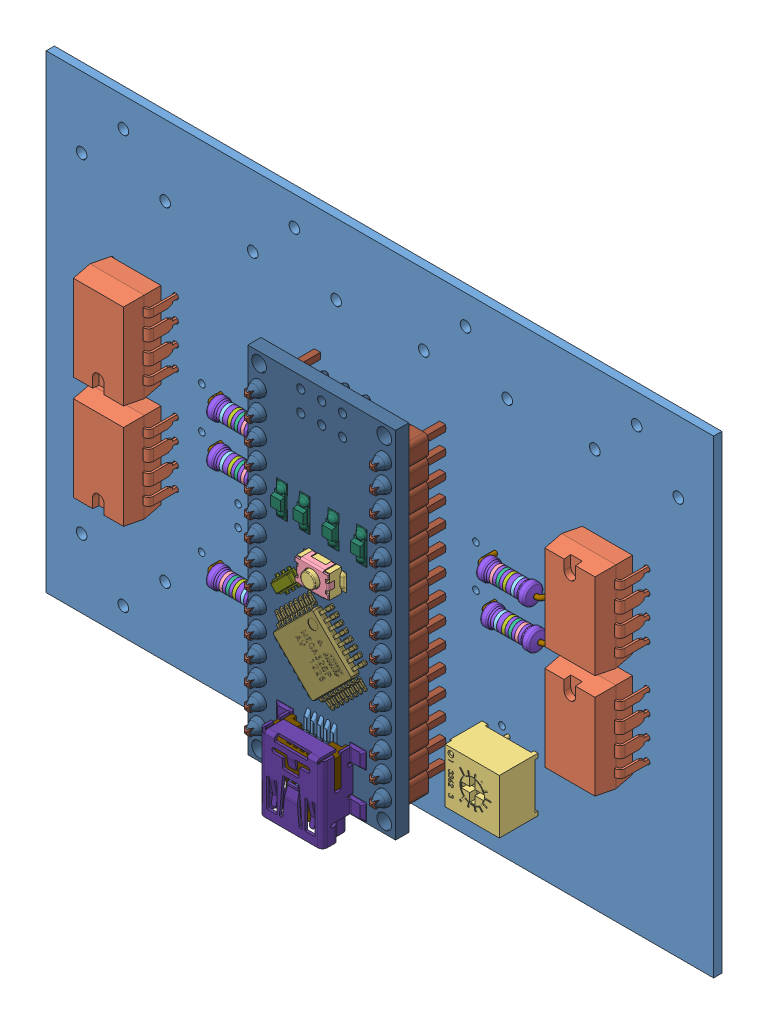
SolidWorks assembly main1, configuration По умолчанию. Lengths in mm.
Overall size (81.26 57.14 14.93).
72 component instances, 26 part files, 23 mates.
Components (placement in the parent):
- main-1: main [По умолчанию] at origin size (81.26 57.14 1)
- DIP 8 IC-1: DIP 8 IC [Default] at (116.08 60.84 1.5) size (7.87 10.92 8.58)
- DIP 8 IC-2: DIP 8 IC [Default] at (116.08 48.14 1.5) size (7.87 10.92 8.58)
- DIP 8 IC-3: DIP 8 IC [Default] at (58.67 47.88 1.5) x (-1 0 0) z (0 0 1) size (7.87 10.92 8.58)
- DIP 8 IC-4: DIP 8 IC [Default] at (58.67 60.58 1.5) x (-1 0 0) z (0 0 1) size (7.87 10.92 8.58)
- 3362H-1: 3362H [Default] at (104.78 36.58 2.47) x (0 -1 0) z (0 0 1) size (6.6 7.05 10.17)
- User Library-CFR-25 CFR50S (300mils)-2-1: User Library-CFR-25 CFR50S (300mils)-2 [Default] at (71.8501 39.141 2.5768) x (0 0 -1) z (0.999985 -0.0055 0) size (5.28 2.4 8.17)
  - User Library-CFR-25 CFR50S (300mils)-2_Band1-1: User Library-CFR-25 CFR50S (300mils)-2_Band1 [Default] at origin size (2.01 2.01 0.4)
  - User Library-CFR-25 CFR50S (300mils)-2_Band4-1: User Library-CFR-25 CFR50S (300mils)-2_Band4 [Default] at origin size (2.01 2.01 0.4)
  - User Library-CFR-25 CFR50S (300mils)-2_Band2-1: User Library-CFR-25 CFR50S (300mils)-2_Band2 [Default] at origin size (2.01 2.01 0.4)
  - User Library-CFR-25 CFR50S (300mils)-2_Band3-1: User Library-CFR-25 CFR50S (300mils)-2_Band3 [Default] at origin size (2.01 2.01 0.4)
  - User Library-CFR-25 CFR50S (300mils)-2_Core-1: User Library-CFR-25 CFR50S (300mils)-2_Core [Default] at origin size (2.4 2.4 6.3)
  - User Library-CFR-25 CFR50S (300mils)-2_Leads-1: User Library-CFR-25 CFR50S (300mils)-2_Leads [Default] at origin size (4.35 0.55 8.17)
- User Library-CFR-25 CFR50S (300mils)-2-2: User Library-CFR-25 CFR50S (300mils)-2 [Default] at (105.2501 51.7882 2.5768) x (0 0 -1) z (-0.999965 -0.008347 0) size (5.28 2.4 8.17)
  - User Library-CFR-25 CFR50S (300mils)-2_Band1-1: User Library-CFR-25 CFR50S (300mils)-2_Band1 [Default] at origin size (2.01 2.01 0.4)
  - User Library-CFR-25 CFR50S (300mils)-2_Band4-1: User Library-CFR-25 CFR50S (300mils)-2_Band4 [Default] at origin size (2.01 2.01 0.4)
  - User Library-CFR-25 CFR50S (300mils)-2_Band2-1: User Library-CFR-25 CFR50S (300mils)-2_Band2 [Default] at origin size (2.01 2.01 0.4)
  - User Library-CFR-25 CFR50S (300mils)-2_Band3-1: User Library-CFR-25 CFR50S (300mils)-2_Band3 [Default] at origin size (2.01 2.01 0.4)
  - User Library-CFR-25 CFR50S (300mils)-2_Core-1: User Library-CFR-25 CFR50S (300mils)-2_Core [Default] at origin size (2.4 2.4 6.3)
  - User Library-CFR-25 CFR50S (300mils)-2_Leads-1: User Library-CFR-25 CFR50S (300mils)-2_Leads [Default] at origin size (4.35 0.55 8.17)
- User Library-CFR-25 CFR50S (300mils)-2-3: User Library-CFR-25 CFR50S (300mils)-2 [Default] at (71.8802 56.9346 2.5768) x (0 0 -1) z (-0.999959 0.009082 0) size (5.28 2.4 8.17)
  - User Library-CFR-25 CFR50S (300mils)-2_Band1-1: User Library-CFR-25 CFR50S (300mils)-2_Band1 [Default] at origin size (2.01 2.01 0.4)
  - User Library-CFR-25 CFR50S (300mils)-2_Band4-1: User Library-CFR-25 CFR50S (300mils)-2_Band4 [Default] at origin size (2.01 2.01 0.4)
  - User Library-CFR-25 CFR50S (300mils)-2_Band2-1: User Library-CFR-25 CFR50S (300mils)-2_Band2 [Default] at origin size (2.01 2.01 0.4)
  - User Library-CFR-25 CFR50S (300mils)-2_Band3-1: User Library-CFR-25 CFR50S (300mils)-2_Band3 [Default] at origin size (2.01 2.01 0.4)
  - User Library-CFR-25 CFR50S (300mils)-2_Core-1: User Library-CFR-25 CFR50S (300mils)-2_Core [Default] at origin size (2.4 2.4 6.3)
  - User Library-CFR-25 CFR50S (300mils)-2_Leads-1: User Library-CFR-25 CFR50S (300mils)-2_Leads [Default] at origin size (4.35 0.55 8.17)
- User Library-CFR-25 CFR50S (300mils)-2-4: User Library-CFR-25 CFR50S (300mils)-2 [Default] at (71.88 51.82 2.5768) x (0 0 -1) z (-1 0 0) size (5.28 2.4 8.17)
  - User Library-CFR-25 CFR50S (300mils)-2_Band1-1: User Library-CFR-25 CFR50S (300mils)-2_Band1 [Default] at origin size (2.01 2.01 0.4)
  - User Library-CFR-25 CFR50S (300mils)-2_Band4-1: User Library-CFR-25 CFR50S (300mils)-2_Band4 [Default] at origin size (2.01 2.01 0.4)
  - User Library-CFR-25 CFR50S (300mils)-2_Band2-1: User Library-CFR-25 CFR50S (300mils)-2_Band2 [Default] at origin size (2.01 2.01 0.4)
  - User Library-CFR-25 CFR50S (300mils)-2_Band3-1: User Library-CFR-25 CFR50S (300mils)-2_Band3 [Default] at origin size (2.01 2.01 0.4)
  - User Library-CFR-25 CFR50S (300mils)-2_Core-1: User Library-CFR-25 CFR50S (300mils)-2_Core [Default] at origin size (2.4 2.4 6.3)
  - User Library-CFR-25 CFR50S (300mils)-2_Leads-1: User Library-CFR-25 CFR50S (300mils)-2_Leads [Default] at origin size (4.35 0.55 8.17)
- User Library-CFR-25 CFR50S (300mils)-2-5: User Library-CFR-25 CFR50S (300mils)-2 [Default] at (105.25 56.9167 3.0768) x (0 0 -1) z (0.99999 -0.004388 0) size (5.28 2.4 8.17)
  - User Library-CFR-25 CFR50S (300mils)-2_Band1-1: User Library-CFR-25 CFR50S (300mils)-2_Band1 [Default] at origin size (2.01 2.01 0.4)
  - User Library-CFR-25 CFR50S (300mils)-2_Band4-1: User Library-CFR-25 CFR50S (300mils)-2_Band4 [Default] at origin size (2.01 2.01 0.4)
  - User Library-CFR-25 CFR50S (300mils)-2_Band2-1: User Library-CFR-25 CFR50S (300mils)-2_Band2 [Default] at origin size (2.01 2.01 0.4)
  - User Library-CFR-25 CFR50S (300mils)-2_Band3-1: User Library-CFR-25 CFR50S (300mils)-2_Band3 [Default] at origin size (2.01 2.01 0.4)
  - User Library-CFR-25 CFR50S (300mils)-2_Core-1: User Library-CFR-25 CFR50S (300mils)-2_Core [Default] at origin size (2.4 2.4 6.3)
  - User Library-CFR-25 CFR50S (300mils)-2_Leads-1: User Library-CFR-25 CFR50S (300mils)-2_Leads [Default] at origin size (4.35 0.55 8.17)
- User Library-arduino_nano-1: User Library-arduino_nano [Default] at (79.76 67.06 6.5) x (0 -1 0) z (-1 0 0) size (45 13.93 18)
  - User Library-arduino_nano_nano-board-1: User Library-arduino_nano_nano-board [Default] at origin size (43.2 4.6 18)
  - User Library-arduino_nano_15pin_header__-1: User Library-arduino_nano_15pin_header__ [Default] x (0 0 1) z (1 0 0) size (2.54 11.75 38.1)
  - User Library-arduino_nano_15pin_header__-2: User Library-arduino_nano_15pin_header__ [Default] at (0 0 -15.24) x (0 0 1) z (1 0 0) size (2.54 11.75 38.1)
  - User Library-arduino_nano_atmega328-1: User Library-arduino_nano_atmega328 [Default] at (23.85 1.75 -7.62) x (-0.707107 0 0.707107) z (-0.707107 0 -0.707107) size (10 1.11 10)
  - User Library-arduino_nano_ftdi FT232rl-1: User Library-arduino_nano_ftdi FT232rl [Default] at (29.05 0 -7.67) x (0 0 -1) z (-1 0 0) size (9.25 1.9 10.2)
  - User Library-arduino_nano_smt_resistor222-1: User Library-arduino_nano_smt_resistor222 [Default] at (21.86 0 -5.8) x (0 0 -1) z (-1 0 0) size (1.7 0.6 3.8)
  - User Library-arduino_nano_smt_resistor222-2: User Library-arduino_nano_smt_resistor222 [Default] at (21.86 0 -9) x (0 0 -1) z (-1 0 0) size (1.7 0.6 3.8)
  - User Library-arduino_nano_smt_resistor222-3: User Library-arduino_nano_smt_resistor222 [Default] at (36.75 0 -7.6) x (0 0 -1) z (-1 0 0) size (1.7 0.6 3.8)
  - User Library-arduino_nano_smt_resistor222-4: User Library-arduino_nano_smt_resistor222 [Default] at (36.75 0 -12) x (0 0 -1) z (-1 0 0) size (1.7 0.6 3.8)
  - User Library-arduino_nano_smt_resistor222-5: User Library-arduino_nano_smt_resistor222 [Default] at (8.2 0 -2.6) x (0 0 -1) z (-1 0 0) size (1.7 0.6 3.8)
  - User Library-arduino_nano_led-1: User Library-arduino_nano_led [Default] at (10.4 1.6 -2.8) size (4 0.9 1.55)
  - User Library-arduino_nano_led-2: User Library-arduino_nano_led [Default] at (10.4 1.6 -5.55) size (4 0.9 1.55)
  - User Library-arduino_nano_led-3: User Library-arduino_nano_led [Default] at (10.4 1.6 -12.5) size (4 0.9 1.55)
  - User Library-arduino_nano_led-4: User Library-arduino_nano_led [Default] at (10.4 1.6 -9.05) size (4 0.9 1.55)
  - User Library-arduino_nano_16mhz crystal - measured-1: User Library-arduino_nano_16mhz crystal - measured [Default] at (18.5113 1.6 -3.5541) x (0.707107 0 0.707107) z (-0.707107 0 0.707107) size (3.4 0.8 2)
  - User Library-arduino_nano_MINIUSBSHELL-1: User Library-arduino_nano_MINIUSBSHELL [Default] at (38.98 1.65 -7.62) x (0 0 1) z (-1 0 0) size (10.9 3.85 9.41)
  - User Library-arduino_nano_MINIUSBCORE-1: User Library-arduino_nano_MINIUSBCORE [Default] at (32.28 1.65 -7.62) x (0 0 -1) z (1 0 0) size (7.7 4.5 8.2)
  - User Library-arduino_nano_MINI USB CONTACT-1: User Library-arduino_nano_MINI USB CONTACT [Default] at (33.28 1.65 -9.22) x (0 0 -1) z (1 0 0) size (0.53 2.55 9.41)
  - User Library-arduino_nano_MINI USB CONTACT-2: User Library-arduino_nano_MINI USB CONTACT [Default] at (33.28 1.65 -8.42) x (0 0 -1) z (1 0 0) size (0.53 2.55 9.41)
  - User Library-arduino_nano_MINI USB CONTACT-3: User Library-arduino_nano_MINI USB CONTACT [Default] at (33.28 1.65 -7.62) x (0 0 -1) z (1 0 0) size (0.53 2.55 9.41)
  - User Library-arduino_nano_MINI USB CONTACT-4: User Library-arduino_nano_MINI USB CONTACT [Default] at (33.28 1.65 -6.82) x (0 0 -1) z (1 0 0) size (0.53 2.55 9.41)
  - User Library-arduino_nano_MINI USB CONTACT-5: User Library-arduino_nano_MINI USB CONTACT [Default] at (33.28 1.65 -6.02) x (0 0 -1) z (1 0 0) size (0.53 2.55 9.41)
  - User Library-arduino_nano_cap106C-1: User Library-arduino_nano_cap106C [Default] at (37.2 0 -3.3) x (0 0 1) z (1 0 0) size (1.7 1.81 4)
  - User Library-arduino_nano_cap106C-2: User Library-arduino_nano_cap106C [Default] at (7.9 0 -5.6) x (0 0 -1) z (-1 0 0) size (1.7 1.81 4)
  - User Library-arduino_nano_reset core-1: User Library-arduino_nano_reset core [Default] at (15.25 1.6 -8.05) x (0 0 -1) z (1 0 0) size (5.2 2.15 2.8)
  - User Library-arduino_nano_reset shell-1: User Library-arduino_nano_reset shell [Default] at (15.25 3.25 -8.05) size (3 1.65 4)
  - User Library-arduino_nano_nano - reg-1: User Library-arduino_nano_nano - reg [Default] at (6.1 0 -10.16) x (0 0 -1) z (-1 0 0) size (6.5 1.69 8.3)
  - User Library-arduino_nano_NANO DIODE-1: User Library-arduino_nano_NANO DIODE [Default] at (11.43 0 -4.2) x (0 0 1) z (1 0 0) size (4.92 1.38 1.7)
  - User Library-arduino_nano_189 RESISTOR PACK-1: User Library-arduino_nano_189 RESISTOR PACK [Default] at (15.75 0 -10.85) x (0 0 1) z (1 0 0) size (3.2 0.51 3)
  - User Library-arduino_nano_102 RESISTOR PACK-1: User Library-arduino_nano_102 RESISTOR PACK [Default] at (15.75 0 -5.2) x (0 0 1) z (1 0 0) size (3.2 0.51 3)
Mates (geometry in assembly coordinates):
- Центр профилей1: profile center = 3 mm: plane of User Library-arduino_nano-1/User Library-arduino_nano_15pin_header__-1 through (79.885 66.935 -2) normal (0 0 -1); circle of main-1
- Центр профилей2: profile center = 3 mm: plane of User Library-arduino_nano-1/User Library-arduino_nano_15pin_header__-2 through (95.125 31.375 -2) normal (0 0 -1); circle of main-1
- Центр профилей3: profile center = 2 mm: plane of DIP 8 IC-1 through (112.145 63.825 -2) normal (0 0 -1); circle of main-1
- Центр профилей4: profile center = 2 mm: plane of DIP 8 IC-1 through (120.015 56.205 -2) normal (0 0 -1); circle of main-1
- Центр профилей6: profile center = 2 mm: plane of DIP 8 IC-2 through (112.145 51.125 -2) normal (0 0 -1); circle of main-1
- Центр профилей7: profile center = 2 mm: plane of DIP 8 IC-2 through (120.015 43.505 -2) normal (0 0 -1); circle of main-1
- Центр профилей8: profile center = 2 mm: plane of DIP 8 IC-4 through (54.735 57.595 -2) normal (0 0 -1); circle of main-1
- Центр профилей9: profile center = 2 mm: plane of DIP 8 IC-4 through (62.605 65.215 -2) normal (0 0 -1); circle of main-1
- Центр профилей10: profile center = 2 mm: plane of DIP 8 IC-3 through (54.735 44.895 -2) normal (0 0 -1); circle of main-1
- Центр профилей11: profile center = 2 mm: plane of DIP 8 IC-3 through (62.605 52.515 -2) normal (0 0 -1); circle of main-1
- Концентричный2: concentric: cylinder of main-1 through (109.06 56.9 1) axis (0 0 -1) radius 0.405; cylinder of ? through (109.06 56.9 2.5) axis (0 0 -1) radius 0.275
- Расстояние3: distance = 1 mm: plane of main-1 through (0 0 0) normal (0 0 -1); plane of ? through (101.3036 57.1722 -1) normal (0 0 -1)
- Концентричный3: concentric: cylinder of main-1 through (109.06 51.82 1) axis (0 0 -1) radius 0.405; cylinder of ? through (109.06 51.82 2) axis (0 0 1) radius 0.275
- Концентричный6: concentric: cylinder of main-1 through (75.69 56.9 1) axis (0 0 -1) radius 0.405; cylinder of ? through (75.69 56.9 2) axis (0 0 1) radius 0.275
- Концентричный7: concentric: cylinder of main-1 through (75.69 51.82 1) axis (0 0 -1) radius 0.405; cylinder of ? through (75.69 51.82 2) axis (0 0 1) radius 0.275
- Расстояние5: distance = 1.5 mm: plane of main-1 through (0 0 0) normal (0 0 -1); plane of ? through (67.9325 51.5818 -1.5) normal (0 0 -1)
- Расстояние6: distance = 1.5 mm: plane of main-1 through (0 0 0) normal (0 0 -1); plane of ? through (67.9307 56.7323 -1.5) normal (0 0 -1)
- Концентричный8: concentric: cylinder of main-1 through (109.06 51.82 1) axis (0 0 -1) radius 0.405; cylinder of ? through (109.06 51.82 2) axis (0 0 1) radius 0.275
- Расстояние7: distance = 1.5 mm: plane of ? through (101.3048 51.5171 -1.5) normal (0 0 -1); plane of main-1 through (0 0 0) normal (0 0 -1)
- Концентричный9: concentric: cylinder of main-1 through (75.66 39.12 1) axis (0 0 -1) radius 0.405; cylinder of ? through (75.66 39.12 2) axis (0 0 -1) radius 0.275
- Расстояние8: distance = 1.5 mm: plane of ? through (67.9039 39.4008 -1.5) normal (0 0 -1); plane of main-1 through (0 0 0) normal (0 0 -1)
- Концентричный10: concentric: cylinder of main-1 through (104.78 36.58 1) axis (0 0 -1) radius 0.405; cylinder of 3362H-1 through (104.78 36.58 -3) axis (0 0 1) radius 0.23
- Расстояние10: distance = 4 mm: plane of 3362H-1 through (104.78 36.58 -3) normal (0 0 -1); plane of main-1 through (0 0 1) normal (0 0 1)
